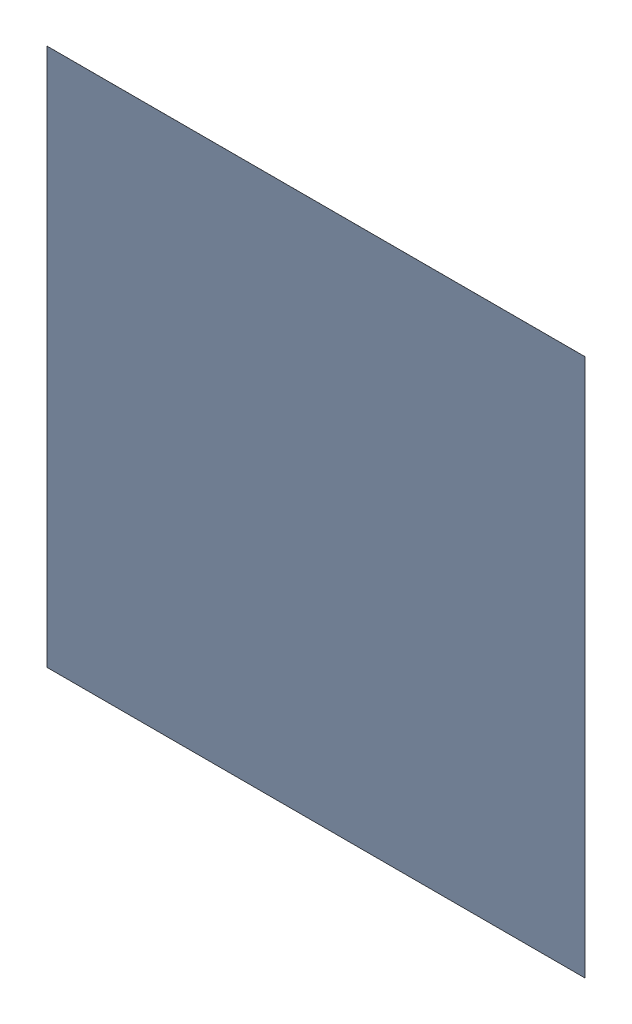
SolidWorks assembly X2, configuration Standard. Lengths in mm.
Overall size (0.05 0.05 0).
2 component instances, 1 part files, 0 mates.
Components (placement in the parent):
- 6269211456-1: 6269211456 [Standard] at (-13.4 -23.5 0) x (0 1 0) z (0 0 1) size (0.05 0.05 0)
  - Extruded-3-1: Extruded-3 [Standard] at origin size (0.05 0.05 0)
